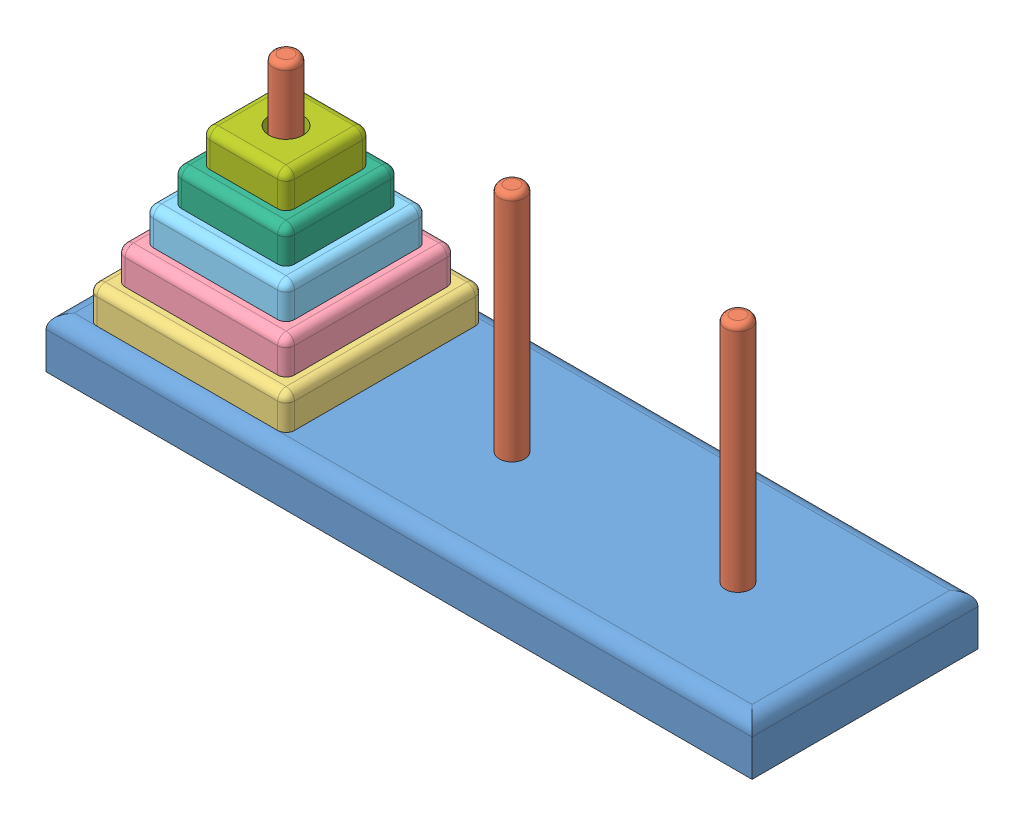
SolidWorks assembly Assem1, configuration Default. Lengths in mm.
Overall size (250 100 80).
9 component instances, 7 part files, 16 mates.
Components (placement in the parent):
- Base Childs Toy-1: Base Childs Toy [Default] at (-0.4688 -14.8747 10.353) size (250 18 80)
- Dowel-1: Dowel [Default] at (-80.4688 -23.8747 10.353) size (9 100 9)
- Dowel-2: Dowel [Default] at (-0.4688 -23.8747 10.353) size (9 100 9)
- Dowel-3: Dowel [Default] at (79.5312 -23.8747 10.353) size (9 100 9)
- Black Block-1: Black Block [Default] at (-80.4688 -5.8747 10.353) size (70 12 70)
- Grey Block-1: Grey Block [Default] at (-80.4688 6.1253 10.353) size (60 12 60)
- Blue Block-1: Blue Block [Default] at (-80.4688 18.1253 10.353) size (50 12 50)
- Red Block-1: Red Block [Default] at (-80.4688 30.1253 10.353) size (40 12 40)
- Green Block-1: Green Block [Default] at (-80.4688 42.1253 10.353) size (30 12 30)
Mates (geometry in assembly coordinates):
- Coincident1: coincident anti-aligned: plane of Base Childs Toy-1 through (-125.4688 -23.8747 -29.647) normal (0 -1 0); circle of Dowel-1
- Coincident2: coincident aligned: circle of Base Childs Toy-1; circle of Dowel-1
- Coincident3: coincident aligned: plane of Base Childs Toy-1 through (-125.4688 -23.8747 -29.647) normal (0 -1 0); plane of Dowel-2 through (-0.4688 -23.8747 10.353) normal (0 -1 0)
- Coincident4: coincident aligned: circle of Base Childs Toy-1; circle of Dowel-2
- Coincident5: coincident aligned: plane of Base Childs Toy-1 through (-125.4688 -23.8747 -29.647) normal (0 -1 0); plane of Dowel-3 through (79.5312 -23.8747 10.353) normal (0 -1 0)
- Coincident6: coincident aligned: circle of Base Childs Toy-1; circle of Dowel-3
- Coincident7: coincident anti-aligned: plane of Base Childs Toy-1 through (-125.4688 -5.8747 -29.647) normal (0 1 0); plane of Black Block-1 through (-112.4688 -5.8747 42.353) normal (0 -1 0)
- Concentric1: concentric aligned: circle of Base Childs Toy-1; circle of Black Block-1
- Coincident8: coincident anti-aligned: plane of Black Block-1 through (-112.4688 6.1253 42.353) normal (0 1 0); plane of Grey Block-1 through (-107.4688 6.1253 37.353) normal (0 -1 0)
- Concentric2: concentric anti-aligned: cylinder of Dowel-1 through (-80.4688 76.1253 10.353) axis (0 -1 0) radius 4.5; circle of Grey Block-1
- Coincident9: coincident anti-aligned: plane of Grey Block-1 through (-107.4688 18.1253 37.353) normal (0 1 0); plane of Blue Block-1 through (-102.4688 18.1253 -11.647) normal (0 -1 0)
- Concentric3: concentric anti-aligned: cylinder of Dowel-1 through (-80.4688 76.1253 10.353) axis (0 -1 0) radius 4.5; circle of Blue Block-1
- Coincident10: coincident anti-aligned: plane of Blue Block-1 through (-102.4688 30.1253 -11.647) normal (0 1 0); plane of Red Block-1 through (-97.4688 30.1253 -6.647) normal (0 -1 0)
- Concentric4: concentric anti-aligned: cylinder of Dowel-1 through (-80.4688 76.1253 10.353) axis (0 -1 0) radius 4.5; circle of Red Block-1
- Coincident11: coincident anti-aligned: plane of Red Block-1 through (-97.4688 42.1253 -6.647) normal (0 1 0); plane of Green Block-1 through (-92.4688 42.1253 -1.647) normal (0 -1 0)
- Concentric5: concentric anti-aligned: cylinder of Dowel-1 through (-80.4688 76.1253 10.353) axis (0 -1 0) radius 4.5; circle of Green Block-1
